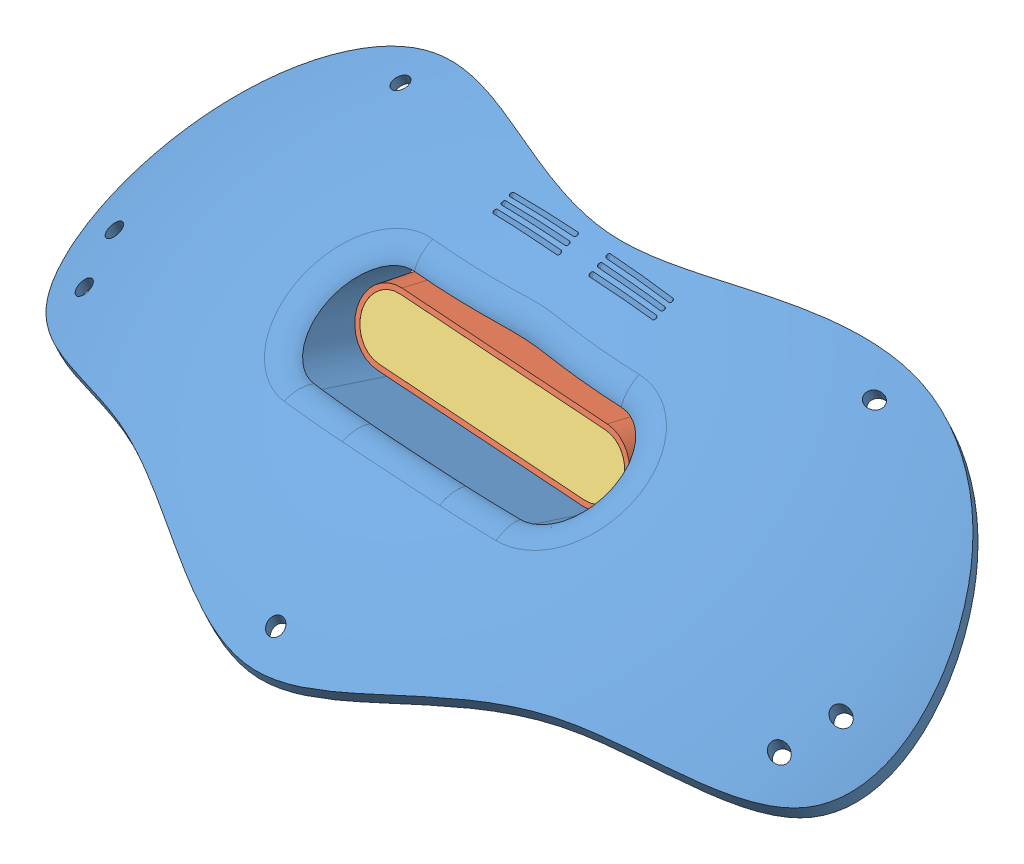
SolidWorks assembly Frente Ensamble, configuration Default. Lengths in mm.
Overall size (294.39 154.79 186.33).
3 component instances, 3 part files, 6 mates.
Components (placement in the parent):
- Pecho-1: Pecho [Default] at (278.4449 223.6551 379.12) x (0.997774 -0.065408 0.013013) z (-0.04109 -0.449268 0.892452) size (284.49 66.63 170.98)
- Realsense-1: Realsense [Default] at (276.874 211.1311 361.7286) x (0.998181 -0.05876 0.013514) z (0.005535 0.312485 0.949907) size (89.45 24.73 25)
- Galss-1: Galss [Default] at (244.5687 220.6967 384.5621) x (0.998181 -0.05876 0.013514) z (0.005535 0.312485 0.949907) size (82.62 17.62 0.5)
Mates (geometry in assembly coordinates):
- Concentric1: concentric: cylinder of assembly; cylinder of assembly; cylinder of Pecho-1 through (281.235 281.7982 346.8782) axis (-0.06004 -0.948104 0.312242) radius 2.5; cylinder of Realsense-1 through (276.6481 209.3645 370.733) axis (-0.06004 -0.948104 0.312242) radius 2.5
- Coincident1: coincident: circle of assembly; circle of assembly; circle of Pecho-1; circle of Realsense-1
- Parallel1: parallel: line of assembly; line of assembly; line of Pecho-1 through (308.5782 198.1513 368.4456) axis (-0.998181 0.05876 -0.013514); line of Realsense-1 through (308.7609 200.4741 365.0486) axis (-0.998181 0.05876 -0.013514)
- Coincident3: coincident: plane of assembly; plane of assembly; plane of Realsense-1 through (277.0096 218.787 385.0013) normal (0.005535 0.312485 0.949907); plane of Galss-1 through (244.5687 220.6967 384.5621) normal (-0.005535 -0.312485 -0.949907)
- Concentric2: concentric: circle of assembly; circle of assembly; circle of Realsense-1; circle of Galss-1
- Concentric3: concentric: circle of assembly; circle of assembly; circle of Realsense-1; circle of Galss-1
